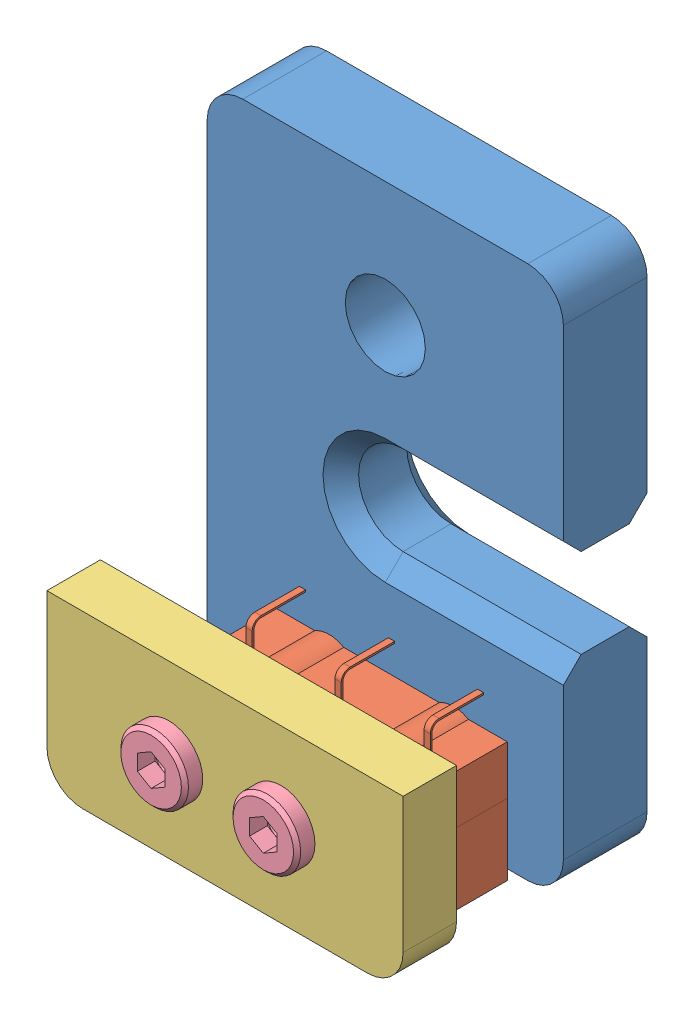
SolidWorks assembly Endstop, configuration Default. Lengths in mm.
Overall size (20 33.22 14.7).
5 component instances, 4 part files, 10 mates.
Components (placement in the parent):
- Endstop Mount-1: Endstop Mount [Default] at origin size (20 30 4.7)
- Microswitch-1: Microswitch [Défaut] at (10.35 -0.575 7.7) x (0 -1 0) z (0 0 1) size (11.12 16.44 8)
- Endstop Plate-1: Endstop Plate [Default] at (0 0 10.7) size (20 9.6 3)
- socket head cap screw_am-4: socket head cap screw_am [B18.3.1M - 2 x 0.4 x 12 Hex SHCS -- 12SHX] at (6.85 4.8 14.7) x (0 0 -1) z (1 0 0) size (14 3.8 3.8)
- socket head cap screw_am-5: socket head cap screw_am [B18.3.1M - 2 x 0.4 x 12 Hex SHCS -- 12SHX] at (13.15 4.8 14.7) x (0 0 -1) z (1 0 0) size (14 3.8 3.8)
Mates (geometry in assembly coordinates):
- Concentric1: concentric: cylinder of Endstop Mount-1 through (6.85 4.8 4.7) axis (0 0 -1) radius 0.75; cylinder of Microswitch-1 through (6.85 4.8 -8.6361) axis (0 0 1) radius 1
- Parallel2: parallel: plane of Endstop Mount-1 through (2 0 4.7) normal (0 -1 0); plane of Microswitch-1 through (16.85 -0.575 10.7) normal (0 -1 0)
- Coincident3: coincident: plane of Endstop Mount-1 through (18 2 4.7) normal (0 0 1); plane of Microswitch-1 through (10.35 -0.575 4.7) normal (0 0 -1)
- Coincident4: coincident: plane of Microswitch-1 through (13.85 4.8 10.7) normal (0 0 1); plane of Endstop Plate-1 through (0 0 10.7) normal (0 0 -1)
- Concentric4: concentric: cylinder of Microswitch-1 through (6.85 4.8 -8.6361) axis (0 0 1) radius 1; cylinder of Endstop Plate-1 through (6.85 4.8 13.7) axis (0 0 -1) radius 1.15
- Concentric5: concentric: cylinder of Endstop Mount-1 through (13.15 4.8 4.7) axis (0 0 -1) radius 0.75; cylinder of Endstop Plate-1 through (13.15 4.8 13.7) axis (0 0 -1) radius 1.15
- Concentric6: concentric: cylinder of Endstop Mount-1 through (6.85 4.8 4.7) axis (0 0 -1) radius 0.75; cylinder of socket head cap screw_am-4 through (6.85 4.8 46.45) axis (0 0 1) radius 1.9
- Concentric7: concentric: cylinder of Endstop Mount-1 through (13.15 4.8 4.7) axis (0 0 -1) radius 0.75; cylinder of socket head cap screw_am-5 through (13.15 4.8 46.45) axis (0 0 1) radius 1.9
- Coincident5: coincident: plane of Endstop Plate-1 through (6.85 4.8 12.7) normal (0 0 1); plane of socket head cap screw_am-4 through (6.85 6.7 12.7) normal (0 0 -1)
- Coincident6: coincident: plane of Endstop Plate-1 through (13.15 4.8 12.7) normal (0 0 1); plane of socket head cap screw_am-5 through (13.15 6.7 12.7) normal (0 0 -1)
